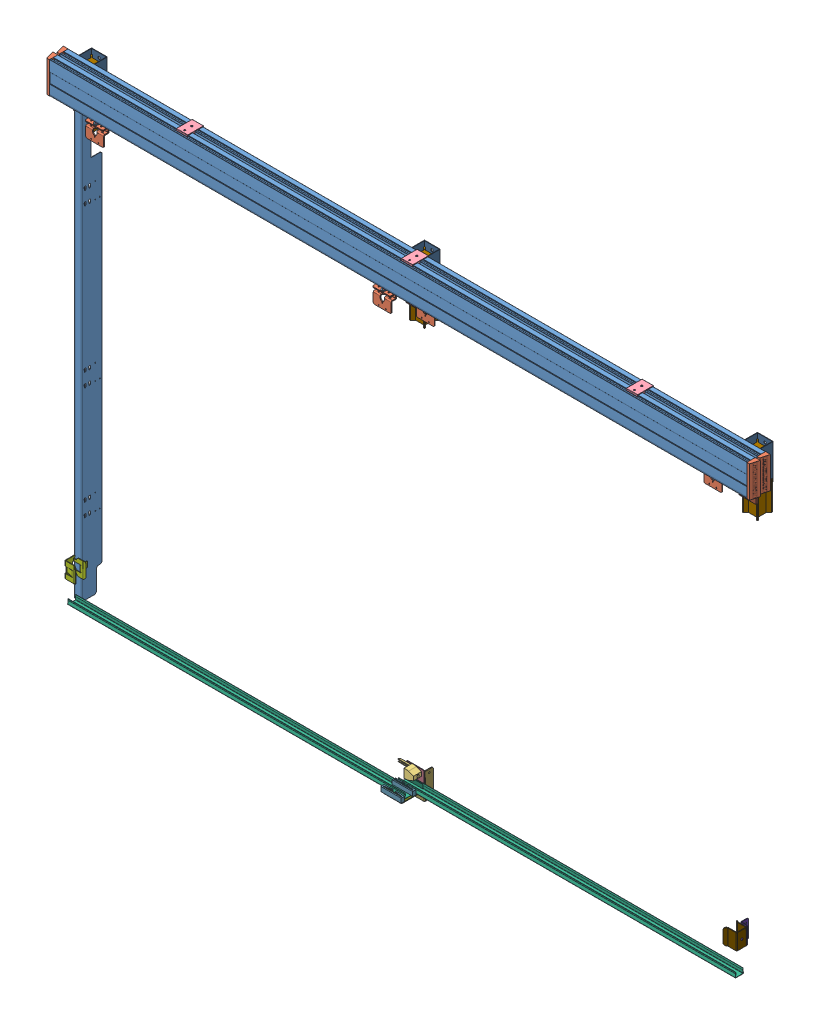
SolidWorks assembly D44-200140-Axelent, configuration Default. Lengths in mm.
Overall size (3144.71 2114.4 183.9).
64 component instances, 22 part files, 0 mates.
Components (placement in the parent):
- D3SB1-XXX(1900)-1: D3SB1-XXX(1900) [Default] at (2.4701 1026.47 31.66) size (33 1890 90.5)
  - G2312 G2313(1900)-1: G2312 G2313(1900) [Default] at (32.5299 18.5325 2.5904) x (-1 0 0) z (0 0 -1) size (33 1890 90.5)
- B20-2K--1: B20-2K- [Default] at (1553.4749 1977.9 66.1) size (80 117.5 30.5)
  - G2311(Default)--1: G2311(Default)- [Default] at origin size (80 70.5 29)
  - G2029--1: G2029- [Default] at (0 59.5 -3) x (0 0 -1) z (1 0 0) size (27 24 75)
  - G2316(B18.3.5M - 8 x 1.25 x 50 Socket FCHS  -- 28S)--1: G2316(B18.3.5M - 8 x 1.25 x 50 Socket FCHS  -- 28S)- [Default] at (0 20.5 -3) x (0 1 0) z (-0.922323 0 0.386419) size (50 15.5 15.5)
  - BRB-10x18x2--1: BRB-10x18x2- [Default] at (0 24.5 -3) size (18 2 18)
- B20-2K--1-1: B20-2K--1 [Default] at (2831.4749 1977.9 66.1) size (80 117.5 30.5)
  - G2311(Default)--1: G2311(Default)- [Default] at origin size (80 70.5 29)
  - G2029--1: G2029- [Default] at (0 59.5 -3) x (0 0 -1) z (1 0 0) size (27 24 75)
  - G2316(B18.3.5M - 8 x 1.25 x 50 Socket FCHS  -- 28S)--1: G2316(B18.3.5M - 8 x 1.25 x 50 Socket FCHS  -- 28S)- [Default] at (0 20.5 -3) x (0 1 0) z (-0.922323 0 0.386419) size (50 15.5 15.5)
  - BRB-10x18x2--1: BRB-10x18x2- [Default] at (0 24.5 -3) size (18 2 18)
- B20-2K--2-1: B20-2K--2 [Default] at (1407.8872 1977.9 111.8) size (80 117.5 30.5)
  - G2311(Default)--1: G2311(Default)- [Default] at origin size (80 70.5 29)
  - G2029--1: G2029- [Default] at (0 59.5 -3) x (0 0 -1) z (1 0 0) size (27 24 75)
  - G2316(B18.3.5M - 8 x 1.25 x 50 Socket FCHS  -- 28S)--1: G2316(B18.3.5M - 8 x 1.25 x 50 Socket FCHS  -- 28S)- [Default] at (0 20.5 -3) x (0 1 0) z (-0.922323 0 0.386419) size (50 15.5 15.5)
  - BRB-10x18x2--1: BRB-10x18x2- [Default] at (0 24.5 -3) size (18 2 18)
- B20-2K--3-1: B20-2K--3 [Default] at (129.8872 1977.9 111.8) size (80 117.5 30.5)
  - G2311(Default)--1: G2311(Default)- [Default] at origin size (80 70.5 29)
  - G2029--1: G2029- [Default] at (0 59.5 -3) x (0 0 -1) z (1 0 0) size (27 24 75)
  - G2316(B18.3.5M - 8 x 1.25 x 50 Socket FCHS  -- 28S)--1: G2316(B18.3.5M - 8 x 1.25 x 50 Socket FCHS  -- 28S)- [Default] at (0 20.5 -3) x (0 1 0) z (-0.922323 0 0.386419) size (50 15.5 15.5)
  - BRB-10x18x2--1: BRB-10x18x2- [Default] at (0 24.5 -3) size (18 2 18)
- D3U2-150(Default)-1: D3U2-150(Default) [Default] at (2192.4749 105.4 62.1) x (0 0 -1) z (1 0 0) size (36.31 22.3 1498)
  - 331-150-000(Default)-1: 331-150-000(Default) [Default] at origin size (36.31 22.3 1498)
- D3U2-150(Default)-1-1: D3U2-150(Default)-1 [Default] at (768.8872 105.4 107.8) x (0 0 -1) z (1 0 0) size (36.31 22.3 1498)
  - 331-150-000(Default)-1: 331-150-000(Default) [Default] at origin size (36.31 22.3 1498)
- B24-4C(Default-_flexible1)-1: B24-4C(Default-_flexible1) [Default] at (-4.7387 299.367 -121.0356) x (0 0 -1) z (0 -1 0) size (74.23 52.06 70.05)
  - G2317(Default)-1: G2317(Default) [Default] at (-228.8356 13.2387 64.3644) x (1 0 0) z (0 1 0) size (74.23 70.05 52.06)
  - G3002-1: G3002 [Default] at (-228.8356 19.4387 64.3644) x (0.930437 0 -0.366451) z (0.366451 0 0.930437) size (19 1.5 19)
- B40-5F--1: B40-5F- [Default] at (0 1992.5 0.1) size (110.5 272.5 79)
  - B00-042-KR--1: B00-042-KR- [Default] at origin size (70 250 70)
  - G2284--1: G2284- [Default] at (0 77.5 0) x (0 0 -1) z (1 0 0) size (70 140 70)
  - Rail_Plate--1: Rail_Plate- [Default] at (0 -55 35) size (110.5 160 9)
- B40-5F--1-1: B40-5F--1 [Default] at (1480 1992.5 0.1) size (110.5 272.5 79)
  - B00-042-KR--1: B00-042-KR- [Default] at origin size (70 250 70)
  - G2284--1: G2284- [Default] at (0 77.5 0) x (0 0 -1) z (1 0 0) size (70 140 70)
  - Rail_Plate--1: Rail_Plate- [Default] at (0 -55 35) size (110.5 160 9)
- B40-5F--2-1: B40-5F--2 [Default] at (2960 1992.5 0.1) size (110.5 272.5 79)
  - B00-042-KR--1: B00-042-KR- [Default] at origin size (70 250 70)
  - G2284--1: G2284- [Default] at (0 77.5 0) x (0 0 -1) z (1 0 0) size (70 140 70)
  - Rail_Plate--1: Rail_Plate- [Default] at (0 -55 35) size (110.5 160 9)
- B40-5B(Default)--1: B40-5B(Default)- [Default] at (1515 109 35) size (91 121.5 98)
  - A-0027387(Default)--1: A-0027387(Default)- [Default] at (0 -57.5 -35) x (-1 0 0) z (0 0 -1) size (74 115 39.19)
  - A-0027428(Default)--1: A-0027428(Default)- [Default] at (5 -10.5 58) x (-1 0 0) z (0 0 -1) size (80 74.5 54)
  - G2305--1: G2305- [Default] at (-35 4.5 58) size (91 20 16.3)
  - G2307--1: G2307- [Default] at (-35 4.5 7) size (80 19.97 5.5)
- B44-4B-1: B44-4B [Default] at (1480 98.5 144) size (91 28.42 105)
  - G2305--1: G2305- [Default] at (0 15 0) size (91 20 16.3)
  - A-0028218(Default)-1: A-0028218(Default) [Default] at (-40 25 0) size (80 28.42 100)
- B40-5C(Default-_flexible1)-1: B40-5C(Default-_flexible1) [Default] at (2925 250 35) x (-1 0 0) z (0 0 1) size (54.01 80 87.6)
  - A-0027956-1: A-0027956 [Default] at origin size (54.01 80 87.6)
    - A-0027749(Default)-1: A-0027749(Default) [Default] at (0 -40 -30) size (28 80 33)
    - G2314-1-1-1: G2314-1-1 [Default] at (-27 0 26) size (54.01 70 63.21)
  - G3002-1: G3002 [Default] at (-22 0 26) x (0 1 0) z (0 0 1) size (19 1.5 19)
- G2382(3100)--1: G2382(3100)- [Default] at (3040 2022.9 62.6) x (0 0 -1) z (1 0 0) size (37.5 140 3100)
- G2382(3100)--2: G2382(3100)- [Default] at (3040 2022.9 108.3) x (0 0 -1) z (1 0 0) size (37.5 140 3100)
- G2384--1: G2384- [Default] at (3040 2092.9 44.1) x (0 0 -1) z (1 0 0) size (37.7 140 22.35)
- G2384--2: G2384- [Default] at (-60 2092.9 89.8) x (0 0 -1) z (-1 0 0) size (37.7 140 22.35)
- G2384--3: G2384- [Default] at (-60 2092.9 44.1) x (0 0 -1) z (-1 0 0) size (37.7 140 22.35)
- G2384--4: G2384- [Default] at (3040 2092.9 89.8) x (0 0 -1) z (1 0 0) size (37.7 140 22.35)
- G2153--1: G2153- [Default] at (1536.8872 205.4 107.8) x (0 0 1) z (1 0 0) size (44.73 40.26 106)
- G2383--1: G2383- [Default] at (515 2162.9 80.9) x (0 0 -1) z (1 0 0) size (72 101.1 50)
- G2383--2: G2383- [Default] at (2515 2162.9 80.9) x (0 0 -1) z (1 0 0) size (72 101.1 50)
- G2383--3: G2383- [Default] at (1515 2162.9 80.9) x (0 0 -1) z (1 0 0) size (72 101.1 50)
